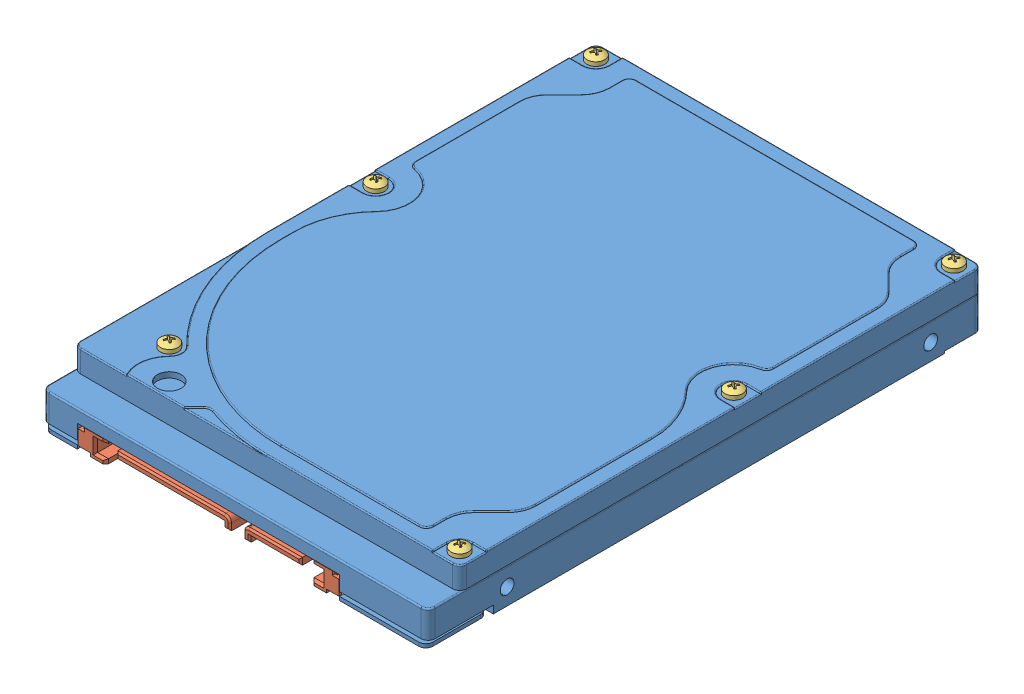
SolidWorks assembly 2.5 HDD, configuration Default. Lengths in mm.
Overall size (71.75 11.67 101.15).
8 component instances, 3 part files, 15 mates.
Components (placement in the parent):
- 2.5 HDD-1: 2.5 HDD [Default] at origin size (71.75 11.67 101.15)
- hdd sata-1: hdd sata [Default] at (31.2138 40.3899 44.1015) x (-1 0 0) z (0 0 1) size (50.93 4 8.5)
- cross recessed pan head screws gb-1: cross recessed pan head screws gb [GB_CROSS_SCREWS_TYPE1 M1.6X3-3  H type-N] at (-32.385 11.6124 -7.7343) x (0 -1 0) z (0.546944 0 -0.837169) size (4.29 3.2 3.2)
- cross recessed pan head screws gb-2: cross recessed pan head screws gb [GB_CROSS_SCREWS_TYPE1 M1.6X3-3  H type-N] at (-25.908 11.6124 36.0807) x (0 -1 0) z (-0.546944 0 0.837169) size (4.29 3.2 3.2)
- cross recessed pan head screws gb-3: cross recessed pan head screws gb [GB_CROSS_SCREWS_TYPE1 M1.6X3-3  H type-N] at (-32.385 11.6124 -47.5615) x (0 -1 0) z (-0.546944 0 0.837169) size (4.29 3.2 3.2)
- cross recessed pan head screws gb-4: cross recessed pan head screws gb [GB_CROSS_SCREWS_TYPE1 M1.6X3-3  H type-N] at (32.385 11.6124 -47.5615) x (0 -1 0) z (0.546944 0 -0.837169) size (4.29 3.2 3.2)
- cross recessed pan head screws gb-5: cross recessed pan head screws gb [GB_CROSS_SCREWS_TYPE1 M1.6X3-3  H type-N] at (32.385 11.6124 -7.7343) x (0 -1 0) z (-0.546944 0 0.837169) size (4.29 3.2 3.2)
- cross recessed pan head screws gb-6: cross recessed pan head screws gb [GB_CROSS_SCREWS_TYPE1 M1.6X3-3  H type-N] at (32.385 11.6124 41.8465) x (0 -1 0) z (-0.546944 0 0.837169) size (4.29 3.2 3.2)
Mates (geometry in assembly coordinates):
- Coincident1: coincident aligned: plane of 2.5 HDD-1 through (0 0 9.4615) normal (0 -1 0); plane of hdd sata-1 through (14.8079 0 45.0417) normal (0 -1 0)
- Coincident2: coincident aligned: plane of 2.5 HDD-1 through (-34.925 6.35 50.1015) normal (0 0 1); plane of hdd sata-1 through (-21.485 2.9202 50.1015) normal (0 0 1)
- Coincident3: coincident anti-aligned: plane of 2.5 HDD-1 through (-4.8 0 0) normal (1 0 0); plane of hdd sata-1
- Concentric8: concentric aligned: circle of 2.5 HDD-1; cylinder of cross recessed pan head screws gb-1 through (-32.385 7.0966 -7.7343) axis (0 -1 0) radius 0.8
- Coincident9: coincident anti-aligned: plane of 2.5 HDD-1 through (0 10.3124 0) normal (0 1 0); plane of cross recessed pan head screws gb-1 through (-33.2222 10.3124 -8.2812) normal (0 -1 0)
- Concentric9: concentric anti-aligned: circle of 2.5 HDD-1; cylinder of cross recessed pan head screws gb-2 through (-25.908 7.0966 36.0807) axis (0 -1 0) radius 0.8
- Coincident10: coincident anti-aligned: plane of 2.5 HDD-1 through (0 10.3124 0) normal (0 1 0); plane of cross recessed pan head screws gb-2 through (-25.0708 10.3124 36.6276) normal (0 -1 0)
- Concentric10: concentric anti-aligned: circle of 2.5 HDD-1; cylinder of cross recessed pan head screws gb-3 through (-32.385 7.0966 -47.5615) axis (0 -1 0) radius 0.8
- Coincident11: coincident anti-aligned: plane of 2.5 HDD-1 through (0 10.3124 0) normal (0 1 0); plane of cross recessed pan head screws gb-3 through (-31.5478 10.3124 -47.0146) normal (0 -1 0)
- Concentric11: concentric aligned: circle of 2.5 HDD-1; cylinder of cross recessed pan head screws gb-4 through (32.385 7.0966 -47.5615) axis (0 -1 0) radius 0.8
- Coincident12: coincident anti-aligned: plane of 2.5 HDD-1 through (0 10.3124 0) normal (0 1 0); plane of cross recessed pan head screws gb-4 through (31.5478 10.3124 -48.1084) normal (0 -1 0)
- Concentric12: concentric anti-aligned: circle of 2.5 HDD-1; cylinder of cross recessed pan head screws gb-5 through (32.385 7.0966 -7.7343) axis (0 -1 0) radius 0.8
- Coincident13: coincident anti-aligned: plane of 2.5 HDD-1 through (0 10.3124 0) normal (0 1 0); plane of cross recessed pan head screws gb-5 through (33.2222 10.3124 -7.1874) normal (0 -1 0)
- Concentric13: concentric anti-aligned: circle of 2.5 HDD-1; cylinder of cross recessed pan head screws gb-6 through (32.385 7.0966 41.8465) axis (0 -1 0) radius 0.8
- Coincident14: coincident anti-aligned: plane of 2.5 HDD-1 through (0 10.3124 0) normal (0 1 0); plane of cross recessed pan head screws gb-6 through (33.2222 10.3124 42.3934) normal (0 -1 0)
